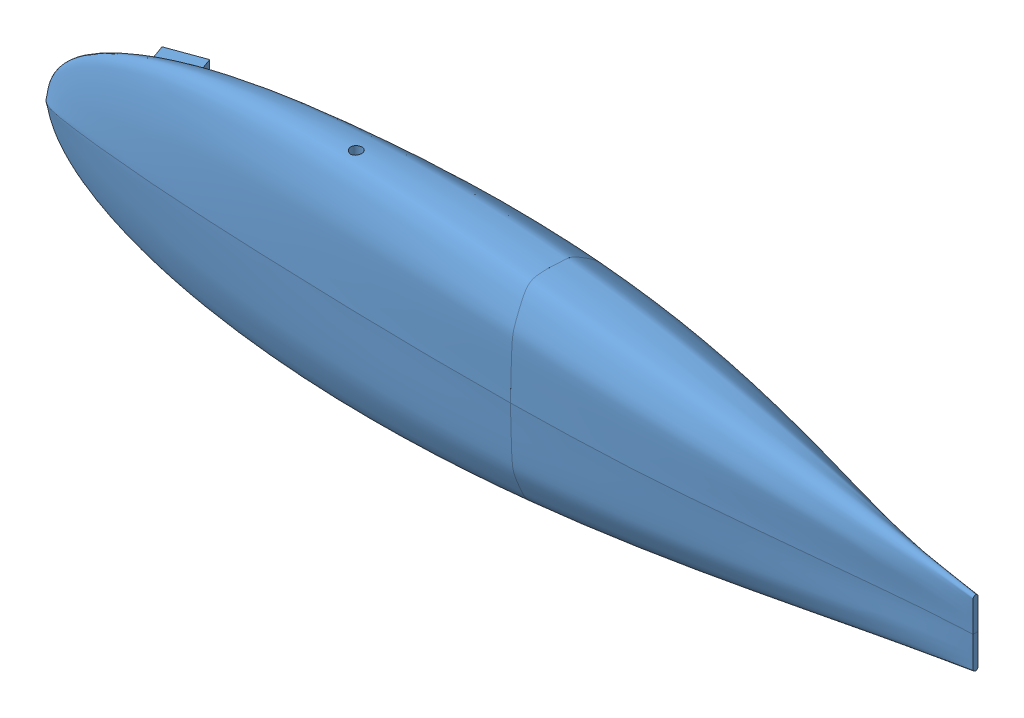
SolidWorks assembly Assem1, configuration Default. Lengths in mm.
Overall size (522.5 153.11 76.33).
4 component instances, 1 part files, 9 mates.
Components (placement in the parent):
- Keel_bulb_Wide-1: Keel_bulb_Wide [Printing Back Right] at (-140.4557 288.9153 446.7814) size (522.49 153.11 75.78)
- Keel_bulb_Wide-2: Keel_bulb_Wide [Printing Front Right] at (-140.4557 288.9153 446.7814) size (281.49 70.22 76.33)
- Keel_bulb_Wide-3: Keel_bulb_Wide [Printing Front Left] at (-140.4557 288.9153 446.7814) size (281.49 70.22 76.33)
- Keel_bulb_Wide-4: Keel_bulb_Wide [Printing Back Left] at (-140.4557 288.9153 446.7814) size (522.49 153.11 75.78)
Mates (geometry in assembly coordinates):
- Concentric1: concentric aligned: cylinder of Keel_bulb_Wide-1 through (119.8943 274.3804 418.5951) axis (1 0 0) radius 4.826; cylinder of Keel_bulb_Wide-2 through (119.8943 274.3804 418.5951) axis (1 0 0) radius 4.826
- Concentric2: concentric aligned: cylinder of Keel_bulb_Wide-1 through (119.8943 274.3804 449.5467) axis (1 0 0) radius 4.826; cylinder of Keel_bulb_Wide-2 through (119.8943 274.3804 449.5467) axis (1 0 0) radius 4.826
- Coincident1: coincident anti-aligned: plane of Keel_bulb_Wide-1 through (138.9443 288.9153 446.7814) normal (-1 0 0); plane of Keel_bulb_Wide-2 through (138.9443 288.9153 446.7814) normal (1 0 0)
- Concentric3: concentric aligned: cylinder of Keel_bulb_Wide-3 through (119.8943 456.558 418.5951) axis (1 0 0) radius 4.826; cylinder of Keel_bulb_Wide-4 through (119.8943 456.558 418.5951) axis (1 0 0) radius 4.826
- Concentric4: concentric aligned: cylinder of Keel_bulb_Wide-3 through (119.8943 456.558 449.5467) axis (1 0 0) radius 4.826; cylinder of Keel_bulb_Wide-4 through (119.8943 456.558 449.5467) axis (1 0 0) radius 4.826
- Coincident2: coincident anti-aligned: plane of Keel_bulb_Wide-3 through (138.9443 442.0231 446.7814) normal (1 0 0); plane of Keel_bulb_Wide-4 through (138.9443 442.0231 446.7814) normal (-1 0 0)
- Concentric5: concentric aligned: cylinder of Keel_bulb_Wide-1 through (232.5592 269.8653 438.1858) axis (0 1 0) radius 4.826; cylinder of Keel_bulb_Wide-4 through (232.5592 269.8653 438.1858) axis (0 1 0) radius 4.826
- Concentric6: concentric aligned: cylinder of Keel_bulb_Wide-2 through (1.0948 269.8653 438.1858) axis (0 1 0) radius 4.826; cylinder of Keel_bulb_Wide-3 through (1.0948 269.8653 438.1858) axis (0 1 0) radius 4.826
- Coincident3: coincident anti-aligned: plane of Keel_bulb_Wide-2 through (382.0223 288.9153 448.1603) normal (0 1 0); plane of Keel_bulb_Wide-3 through (382.0223 288.9153 448.1603) normal (0 -1 0)
